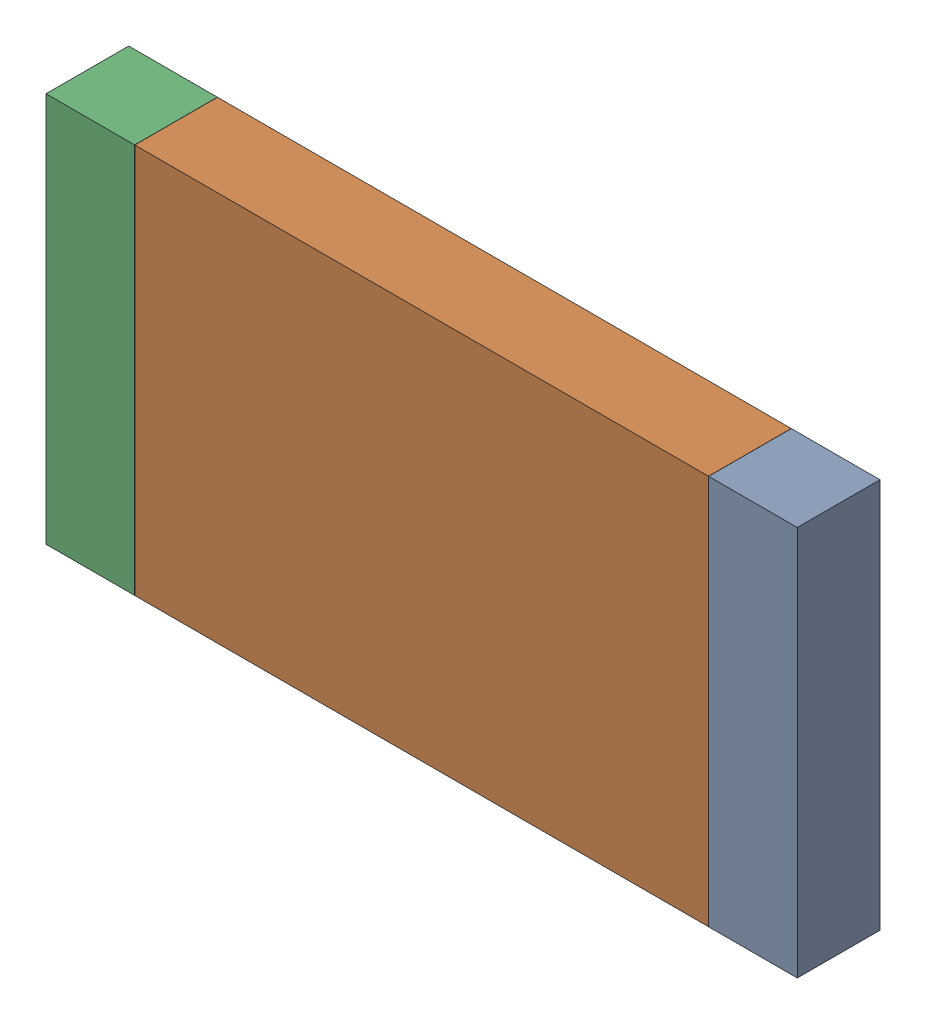
SolidWorks assembly R6, configuration Default. Lengths in mm.
Overall size (6.45 3.35 0.71).
6 component instances, 2 part files, 0 mates.
Components (placement in the parent):
- 6638401968-1: 6638401968 [Default] at (43.611 35.814 0) size (0.76 3.35 0.71)
  - Extruded_10-1: Extruded_10 [Default] at origin size (0.76 3.35 0.71)
- 6638401808-1: 6638401808 [Default] at (40.767 35.814 0) size (4.92 3.35 0.71)
  - Extruded_11-1: Extruded_11 [Default] at origin size (4.92 3.35 0.71)
- 6638401968-2: 6638401968 [Default] at (37.923 35.814 0) size (0.76 3.35 0.71)
  - Extruded_10-1: Extruded_10 [Default] at origin size (0.76 3.35 0.71)
